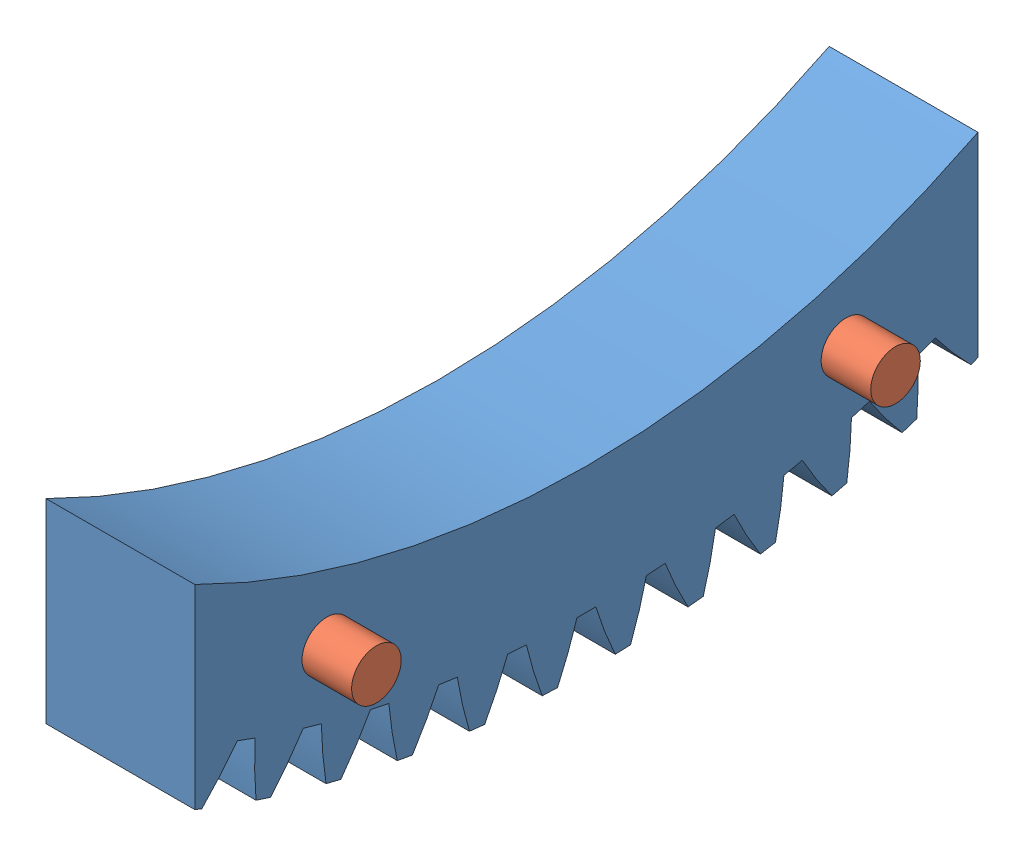
SolidWorks assembly gear_2, configuration Default. Lengths in mm.
Overall size (12 16.37 47.38).
3 component instances, 2 part files, 2 mates.
Components (placement in the parent):
- Metric - Spur gear 1.375M 90T 20PA 9FW ---S90N75H50L105N-1: Metric - Spur gear 1.375M 90T 20PA 9FW ---S90N75H50L105N [Metric - Spur gear 1.375M 90T 20PA 9FW ---S90N75H50L105N] at (-10.4468 8.1502 10.9975) size (9 126.45 126.5)
- insert-1: insert [Default] at (1.5532 -45.9325 -4.7028) x (0 1 0) z (0 0 1) size (3 3 3)
- insert-2: insert [Default] at (1.5532 -45.9023 26.7009) x (0 -0.381849 0.924225) z (0 -0.924225 -0.381849) size (3 3 3)
Mates (geometry in assembly coordinates):
- Coincident1: coincident anti-aligned: circle of insert-1; circle of assembly
- Coincident2: coincident aligned: circle of insert-2; circle of assembly
